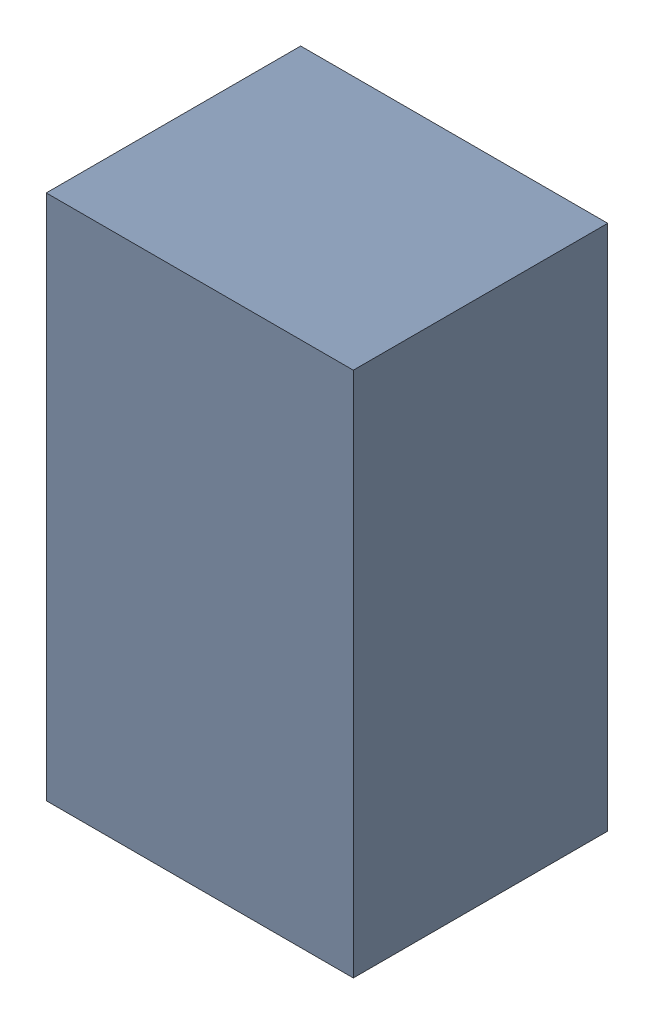
SolidWorks assembly U1-2, configuration Default. Lengths in mm.
Overall size (1.75 3 1.45).
2 component instances, 1 part files, 0 mates.
Components (placement in the parent):
- 959209616-2-1: 959209616-2 [Default] at (137.668 84.449 0) size (1.75 3 1.45)
  - Extruded-89-1: Extruded-89 [Default] at origin size (1.75 3 1.45)
